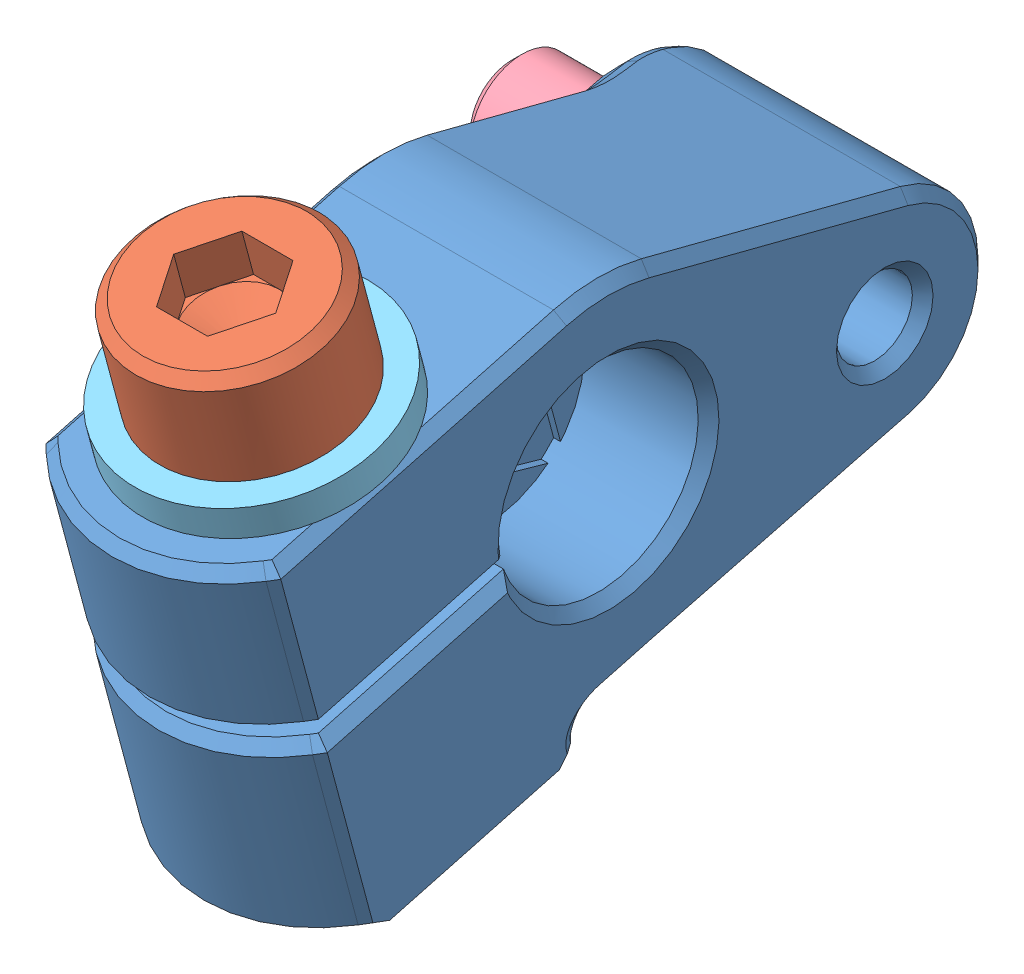
SolidWorks assembly Servo Horn, configuration Default. Lengths in mm.
Overall size (11.01 16.09 21.97).
5 component instances, 5 part files, 8 mates.
Components (placement in the parent):
- Servo Horn-1: Servo Horn [Default] at origin size (8.01 13.24 21.97)
- socket head cap screw_am-1: socket head cap screw_am [B18.3.1M - 3 x 0.5 x 12 Hex SHCS -- 12NHX] at (-3.4 7.1474 7.7127) x (0 -0.965926 -0.258819) z (0 0.258819 -0.965926) size (15 5.5 5.5)
- 94180A331_HEAT-SET INSERTS FOR PLASTICS-1: 94180A331_HEAT-SET INSERTS FOR PLASTICS [Default] at (-3.4 -7.1483 3.8822) x (1 0 0) z (0 0.258819 -0.965926) size (5.56 4.12 5.56)
- Dowel Pin 3mm-1: Dowel Pin 3mm [9mm] at (-6.3 0 -8) x (0 0 -1) z (1 0 0) size (3 3 9)
- flat washer narrow_am-1: flat washer narrow_am [B18.22M - Plain washer, 3 mm, narrow] at (-3.4 4.2496 6.9362) x (0 0.965926 0.258819) z (0 0.258819 -0.965926) size (0.9 7 7)
Mates (geometry in assembly coordinates):
- Concentric1: concentric aligned: cylinder of Servo Horn-1 through (-3.4 -10.8745 2.8837) axis (0 0.965926 0.258819) radius 1.7; cylinder of socket head cap screw_am-1 through (-3.4 37.8155 15.9302) axis (0 0.965926 0.258819) radius 1.5
- Concentric2: concentric anti-aligned: cylinder of Servo Horn-1 through (-3.4 -12.6993 2.3948) axis (0 0.965926 0.258819) radius 2.35; cylinder of 94180A331_HEAT-SET INSERTS FOR PLASTICS-1 through (-3.4 -7.1483 3.8822) axis (0 -0.965926 -0.258819) radius 2.58
- Coincident2: coincident aligned: plane of Servo Horn-1 through (-3.4 -7.1483 3.8822) normal (0 -0.965926 -0.258819); plane of 94180A331_HEAT-SET INSERTS FOR PLASTICS-1 through (-3.4 -7.1483 3.8822) normal (0 -0.965926 -0.258819)
- Concentric3: concentric anti-aligned: cylinder of Servo Horn-1 through (-6.8 0 -8) axis (1 0 0) radius 1.6; cylinder of Dowel Pin 3mm-1 through (-1.8 0 -8) axis (-1 0 0) radius 1.5
- Coincident3: coincident anti-aligned: plane of Servo Horn-1 through (-1.8 0 -8) normal (-1 0 0); plane of Dowel Pin 3mm-1 through (-1.8 0 -8) normal (1 0 0)
- Concentric4: concentric anti-aligned: cylinder of Servo Horn-1 through (-3.4 -10.8745 2.8837) axis (0 0.965926 0.258819) radius 1.7; cylinder of flat washer narrow_am-1 through (-3.4 -29.4854 -2.103) axis (0 -0.965926 -0.258819) radius 1.84
- Coincident4: coincident anti-aligned: plane of Servo Horn-1 through (-6.8 4.8296 1.2941) normal (0 0.965926 0.258819); plane of flat washer narrow_am-1 through (0.1 3.3802 6.7033) normal (0 -0.965926 -0.258819)
- Coincident5: coincident anti-aligned: plane of socket head cap screw_am-1 through (-6.15 4.2496 6.9362) normal (0 -0.965926 -0.258819); plane of flat washer narrow_am-1 through (-1.56 4.2496 6.9362) normal (0 0.965926 0.258819)
